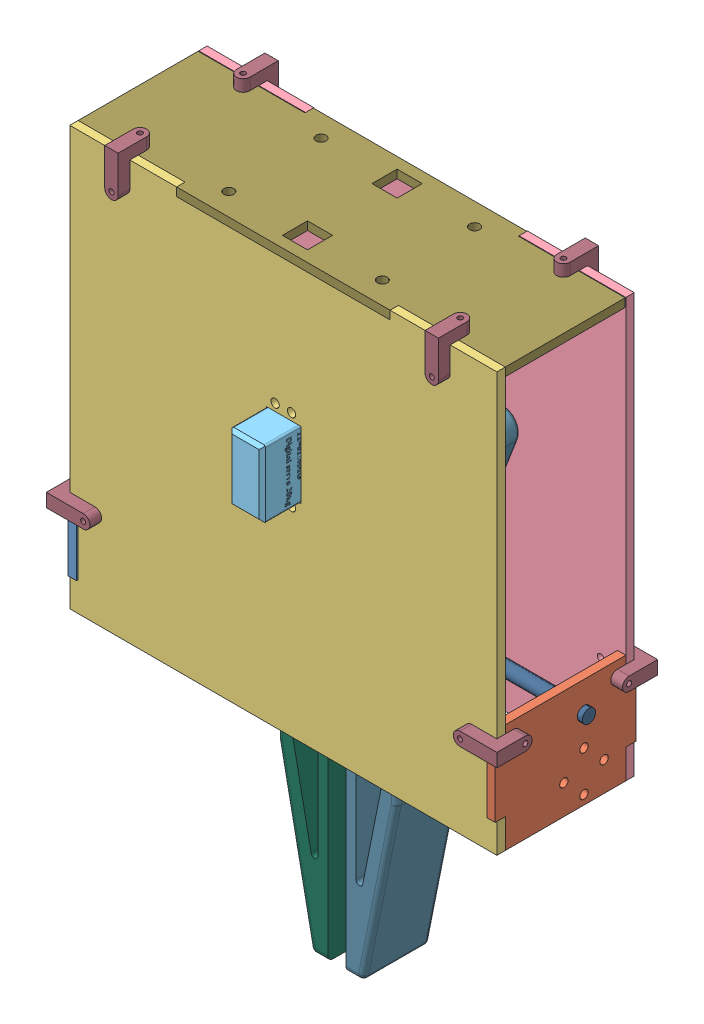
SolidWorks assembly Assem1_mica, configuration Default. Lengths in mm.
Overall size (269 394.5 111.5).
24 component instances, 17 part files, 39 mates.
Components (placement in the parent):
- Part2_mica-1: Part2_mica [Default] at (-23.3552 62.664 78.9474) x (0 0 -1) z (1 0 0) size (84 65 5)
- Part2_mica - Copy-1: Part2_mica - Copy [Default] at (231.6448 127.664 78.9474) x (0 0 -1) z (-1 0 0) size (84 65 5)
- Part1_mica-2: Part1_mica [Default] at (106.6448 187.664 100.9474) size (255 250 5)
- Part3_mica-1: Part3_mica [Default] at (-23.3552 127.664 28.9474) x (1 0 0) z (0 1 0) size (255 5 250)
- Servo 20 kg.stp-1: Servo 20 kg.stp [Default] at (114.1448 225.964 128.4474) x (1 0 0) z (0 1 0) size (20 45.5 54.5)
- Part4-3 - Copy-1: Part4-3 - Copy [Default] at (140.0657 211.2903 55.9474) x (0.998697 -0.051034 0) z (-0.051034 -0.998697 0) size (115.5 24 40)
- Part4-3-1: Part4-3 [Default] at (68.2239 221.0377 55.9474) x (-0.998703 0.050906 0) z (0.050906 0.998703 0) size (115.5 24 40)
- Part2-1: Part2 [Default] at (226.6448 80.164 53.9474) x (0 0 -1) z (0 1 0) size (32 13 32)
- Part2 - Copy-1: Part2 - Copy [Default] at (-18.3552 110.164 53.9474) x (0 0 -1) z (0 -1 0) size (32 13 32)
- Part3 - Copy-2: Part3 - Copy [Default] at (-15.3552 110.164 53.9474) size (250 8 8)
- Part3-2: Part3 [Default] at (-26.3552 80.164 53.9474) x (1 0 0) z (0 -0.29044 0.956893) size (250 8 8)
- Part4-1: Part4 [Default] at (-23.3552 307.664 100.9474) x (1 0 0) z (0 1 0) size (255 81.64 5)
- Part6-1: Part6 [Default] at (199.7698 312.664 24.3097) x (-1 0 0) z (0 0 -1) size (8 26 21)
- Part6-2: Part6 [Default] at (199.7698 312.664 105.9474) size (8 26 21)
- Part6-3: Part6 [Default] at (8.5198 312.664 24.3097) x (-1 0 0) z (0 0 -1) size (8 26 21)
- Part6-4: Part6 [Default] at (-23.3552 118.914 24.8917) x (0 -1 0) z (0 0 -1) size (8 26 21)
- Part6-5: Part6 [Default] at (-23.3552 118.914 105.9474) x (0 1 0) z (0 0 1) size (8 26 21)
- Part6-6: Part6 [Default] at (231.6448 118.914 23.9474) x (0 1 0) z (0 0 -1) size (8 26 21)
- Part6-7: Part6 [Default] at (231.6448 118.914 105.9474) x (0 -1 0) z (0 0 1) size (8 26 21)
- Part6-8: Part6 [Default] at (8.5198 312.664 105.9474) size (8 26 21)
- Part1.1-print-1: Part1.1-print [Default] at (109.5805 50.164 53.9474) x (0 0 -1) z (0 1 0) size (40 64.01 301.01)
- Part1-print-1: Part1-print [Default] at (98.7381 50.164 53.9474) x (0 0 1) z (0 1 0) size (40 64.01 301)
- Part1-4: Part1 [Default] at (104.1448 216.164 83.9474) x (-0.990921 0.134447 0) z (0 0 -1) size (24.6 24.6 6)
- Part5-2: Part5 [Default] at (104.1448 216.164 70.9474) x (0.990921 -0.134447 0) z (-0.134447 -0.990921 0) size (92.5 10 20)
Mates (geometry in assembly coordinates):
- Coincident1: coincident anti-aligned: plane of Part2_mica - Copy-1 through (226.6448 127.664 78.9474) normal (-1 0 0); plane of Part2-1 through (226.6448 80.164 53.9474) normal (1 0 0)
- Coincident4: coincident anti-aligned: plane of Part2_mica - Copy-1 through (226.6448 127.664 78.9474) normal (-1 0 0); plane of Part1_mica-2 through (226.6448 110.164 110.9474) normal (1 0 0)
- Coincident7: coincident anti-aligned: plane of Part2_mica - Copy-1 through (296.6525 62.664 100.9474) normal (0 0 1); plane of Part1_mica-2 through (106.6448 187.664 100.9474) normal (0 0 -1)
- Coincident8: coincident aligned: plane of Part2_mica - Copy-1 through (226.6448 62.664 78.9474) normal (0 -1 0); plane of Part1_mica-2 through (-23.3552 62.664 105.9474) normal (0 -1 0)
- Coincident9: coincident anti-aligned: plane of Part2_mica-1 through (-18.3552 62.664 78.9474) normal (1 0 0); plane of Part2 - Copy-1 through (-18.3552 110.164 53.9474) normal (-1 0 0)
- Coincident10: coincident anti-aligned: plane of Part2_mica-1 through (-18.3552 62.664 78.9474) normal (1 0 0); plane of Part1_mica-2 through (-18.3552 187.664 110.9474) normal (-1 0 0)
- Coincident11: coincident aligned: plane of Part2_mica-1 through (-18.3552 62.664 78.9474) normal (0 -1 0); plane of Part1_mica-2 through (-23.3552 62.664 105.9474) normal (0 -1 0)
- Coincident12: coincident anti-aligned: plane of Part2_mica-1 through (46.6525 127.664 100.9474) normal (0 0 1); plane of Part1_mica-2 through (106.6448 187.664 100.9474) normal (0 0 -1)
- Coincident13: coincident anti-aligned: plane of Part2 - Copy-1 through (-15.3552 110.164 53.9474) normal (1 0 0); plane of Part3 - Copy-2 through (-15.3552 110.164 53.9474) normal (-1 0 0)
- Concentric5: concentric aligned: cylinder of Part2 - Copy-1 through (-5.3552 110.164 53.9474) axis (-1 0 0) radius 4; cylinder of Part3 - Copy-2 through (234.6448 110.164 53.9474) axis (-1 0 0) radius 4
- Concentric6: concentric anti-aligned: cylinder of Part2-1 through (213.6448 80.164 53.9474) axis (1 0 0) radius 4; cylinder of Part3-2 through (223.6448 80.164 53.9474) axis (-1 0 0) radius 4
- Coincident14: coincident anti-aligned: plane of Part2-1 through (223.6448 80.164 53.9474) normal (-1 0 0); plane of Part3-2 through (223.6448 80.164 53.9474) normal (1 0 0)
- Concentric7: concentric aligned: cylinder of Part3 - Copy-2 through (234.6448 110.164 53.9474) axis (-1 0 0) radius 4; cylinder of Part1.1-print-1 through (139.5805 110.164 53.9474) axis (-1 0 0) radius 7.5
- Concentric8: concentric aligned: cylinder of Part3-2 through (223.6448 80.164 53.9474) axis (-1 0 0) radius 4; cylinder of Part1.1-print-1 through (139.5805 80.164 53.9474) axis (-1 0 0) radius 7.5
- Concentric9: concentric anti-aligned: cylinder of Part3-2 through (223.6448 80.164 53.9474) axis (-1 0 0) radius 4; cylinder of Part1-print-1 through (68.7381 80.164 53.9474) axis (1 0 0) radius 7.5
- Concentric10: concentric anti-aligned: cylinder of Part3 - Copy-2 through (234.6448 110.164 53.9474) axis (-1 0 0) radius 4; cylinder of Part1-print-1 through (68.7381 110.164 53.9474) axis (1 0 0) radius 7.5
- Coincident15: coincident anti-aligned: plane of Part4-3-1 through (68.2239 221.0377 55.9474) normal (0 0 -1); plane of Part1.1-print-1 through (163.6001 216.1762 55.9474) normal (0 0 1)
- Coincident16: coincident anti-aligned: plane of Part4-3 - Copy-1 through (140.0657 211.2903 55.9474) normal (0 0 -1); plane of Part1-print-1 through (44.7259 216.164 55.9474) normal (0 0 1)
- Concentric15: concentric aligned: cylinder of Part1_mica-2 through (109.0448 230.264 123.9474) axis (0 0 -1) radius 2.5; cylinder of Servo 20 kg.stp-1 through (109.0448 230.264 100.9474) axis (0 0 -1) radius 2.5
- Concentric16: concentric aligned: cylinder of Part1_mica-2 through (99.2448 230.264 123.9474) axis (0 0 -1) radius 2.5; cylinder of Servo 20 kg.stp-1 through (99.2448 230.264 100.9474) axis (0 0 -1) radius 2.5
- Coincident19: coincident anti-aligned: plane of Part1_mica-2 through (106.6448 187.664 100.9474) normal (0 0 -1); plane of Servo 20 kg.stp-1 through (104.1448 229.589 100.9474) normal (0 0 1)
- Coincident21: coincident anti-aligned: plane of Part2_mica - Copy-1 through (226.6448 127.664 78.9474) normal (-1 0 0); plane of Part3_mica-1 through (226.6448 110.164 33.9474) normal (1 0 0)
- Coincident22: coincident anti-aligned: plane of Part2_mica - Copy-1 through (226.6448 127.664 28.9474) normal (0 0 -1); plane of Part3_mica-1 through (-23.3552 127.664 28.9474) normal (0 0 1)
- Coincident23: coincident aligned: plane of Part2_mica - Copy-1 through (226.6448 62.664 78.9474) normal (0 -1 0); plane of Part3_mica-1 through (-23.3552 62.664 23.9474) normal (0 -1 0)
- Coincident24: coincident anti-aligned: plane of Part3_mica-1 through (104.1448 307.664 208.9474) normal (0 1 0); plane of Part4-1 through (-23.3552 307.664 100.9474) normal (0 -1 0)
- Coincident25: coincident anti-aligned: plane of Part1_mica-2 through (106.6448 187.664 100.9474) normal (0 0 -1); plane of Part4-1 through (-23.3552 312.664 100.9474) normal (0 0 1)
- Coincident26: coincident anti-aligned: plane of Part3_mica-1 through (40.3948 307.664 208.9474) normal (1 0 0); plane of Part4-1 through (40.3948 312.664 100.9474) normal (-1 0 0)
- Coincident27: coincident anti-aligned: plane of Servo 20 kg.stp-1 through (104.1448 216.164 86.9474) normal (0 0 -1); plane of Part1-4 through (104.1448 216.164 86.9474) normal (0 0 1)
- Concentric36: concentric aligned: cylinder of Servo 20 kg.stp-1 through (104.1448 216.164 86.9474) axis (0 0 -1) radius 3; cylinder of Part1-4 through (104.1448 216.164 86.9474) axis (0 0 -1) radius 3
- Concentric37: concentric anti-aligned: cylinder of Part4-3-1 through (68.2239 221.0377 79.9474) axis (0 0 -1) radius 4.5; cylinder of Part5-2 through (68.2239 221.0377 56.8052) axis (0 0 1) radius 4.5
- Concentric38: concentric anti-aligned: cylinder of Part4-3 - Copy-1 through (140.0657 211.2903 79.9474) axis (0 0 -1) radius 4.5; cylinder of Part5-2 through (140.0657 211.2903 56.8052) axis (0 0 1) radius 4.5
- Concentric39: concentric aligned: cylinder of Part1-4 through (97.2084 217.1052 80.9474) axis (0 0 1) radius 1.5; cylinder of Part5-2 through (97.2084 217.1052 70.9474) axis (0 0 1) radius 2
- Concentric42: concentric aligned: cylinder of Part1-4 through (111.0813 215.2229 80.9474) axis (0 0 1) radius 1.5; cylinder of Part5-2 through (111.0813 215.2229 70.9474) axis (0 0 1) radius 2
- Coincident28: coincident anti-aligned: plane of Part1-4 through (104.1448 216.164 80.9474) normal (0 0 -1); plane of Part5-2 through (104.1448 216.164 80.9474) normal (0 0 1)
- Concentric44: concentric anti-aligned: cylinder of Part2_mica-1 through (-28.3552 110.164 41.9474) axis (1 0 0) radius 2.5; cylinder of Part2 - Copy-1 through (-15.3552 110.164 41.9474) axis (-1 0 0) radius 2
- Concentric45: concentric aligned: cylinder of Part2_mica-1 through (-28.3552 98.164 53.9474) axis (1 0 0) radius 2.5; cylinder of Part2 - Copy-1 through (-25.3552 98.164 53.9474) axis (1 0 0) radius 2
- Concentric46: concentric aligned: cylinder of Part2_mica - Copy-1 through (236.6448 92.164 53.9474) axis (-1 0 0) radius 2.5; cylinder of Part2-1 through (282.6448 92.164 53.9474) axis (-1 0 0) radius 2
- Symmetric1: symmetric aligned: cylinder of Part4-3 - Copy-1 through (44.6901 216.164 67.9474) axis (0 0 -1) radius 5; cylinder of Part1-print-1 through (44.6901 216.164 41.8052) axis (0 0 1) radius 5; plane of Part1-print-1 through (48.7259 216.164 53.9474) normal (0 0 1)
- Concentric47: concentric anti-aligned: cylinder of Part4-3-1 through (163.6001 216.1762 67.9474) axis (0 0 -1) radius 5; cylinder of Part1.1-print-1 through (163.6001 216.1762 41.8052) axis (0 0 1) radius 5
